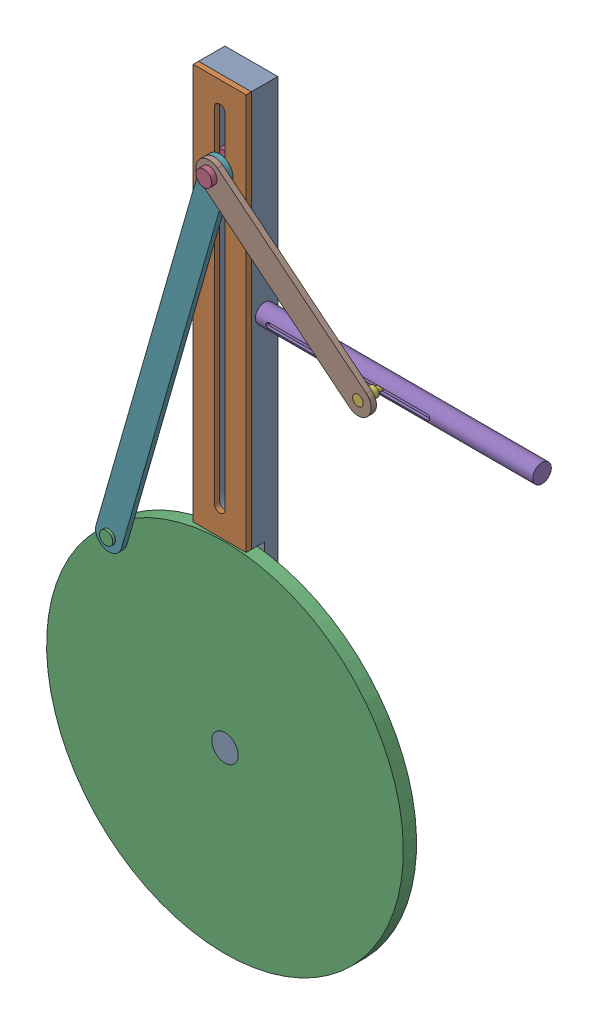
SolidWorks assembly Assem2, configuration Default. Lengths in mm.
Overall size (209.74 314.74 18).
8 component instances, 8 part files, 18 mates.
Components (placement in the parent):
- Base-1: Base [Default] at origin size (20 230 10)
- Rail Lid-1: Rail Lid [Default] at (0 -75 7) x (-1 0 0) z (0 -1 0) size (20 7 150)
- Wheel-1: Wheel [Default] at (0 -220 2.5) x (0.788618 0.614883 0) z (0 0 1) size (135 135 10)
- Cylinder Connector-1: Cylinder Connector [Default] at (0 -29.3569 0) x (-0.943808 -0.330495 0) z (-0.330495 0.943808 0) size (10 13 10)
- Piston Cylinder-1: Piston Cylinder [Default] at (50 -75 0) size (107 7 7)
- Piston-1: Piston [Default] at (56.329 -75 5) size (42 5 13.5)
- Large Link-1: Large Link [Default] at (-19.9837 -99.0484 7) x (-0.961262 0.275637 0) z (0 0 1) size (10 155 2)
- Small Link-1: Small Link [Default] at (56.329 -75 9) x (-0.62956 -0.776952 0) z (0 0 1) size (10 82.5 2)
Mates (geometry in assembly coordinates):
- Concentric1: concentric aligned: cylinder of Base-1 through (-7 -3.5 0) axis (0 0 1) radius 1.5; cylinder of Rail Lid-1 through (-7 -3.5 0) axis (0 0 1) radius 1.5
- Concentric2: concentric aligned: cylinder of Base-1 through (7 -146.5 0) axis (0 0 1) radius 1.5; cylinder of Rail Lid-1 through (7 -146.5 0) axis (0 0 1) radius 1.5
- Coincident1: coincident anti-aligned: plane of Base-1 through (0 -75 5) normal (0 0 1); plane of Rail Lid-1 through (0 -75 5) normal (0 0 -1)
- Concentric3: concentric aligned: cylinder of Base-1 through (0 -220 5) axis (0 0 -1) radius 5; cylinder of Wheel-1 through (0 -220 5) axis (0 0 -1) radius 5
- Coincident2: coincident anti-aligned: plane of Base-1 through (0 -220 0) normal (0 0 1); plane of Wheel-1 through (0 -220 0) normal (0 0 -1)
- Coincident3: coincident anti-aligned: plane of Base-1 through (0 -140 0) normal (0 0 1); plane of Cylinder Connector-1 through (0 -12.5861 0) normal (0 0 -1)
- Tangent1: tangent anti-aligned: plane of Base-1 through (-5 -140 0) normal (1 0 0); cylinder of Cylinder Connector-1 through (0 -12.5861 5) axis (0 0 -1) radius 5
- Concentric4: concentric aligned: cylinder of Base-1 through (8 -75 0) axis (1 0 0) radius 1.5; cylinder of Piston Cylinder-1 through (8 -75 0) axis (1 0 0) radius 1.5
- Coincident5: coincident anti-aligned: plane of Base-1 through (10 -150 5) normal (1 0 0); plane of Piston Cylinder-1 through (10 -75 0) normal (-1 0 0)
- Parallel1: parallel anti-aligned: plane of Base-1 through (-10 0 5) normal (0 1 0); plane of Piston Cylinder-1 through (15 -74 3.5) normal (0 -1 0)
- Concentric5: concentric aligned: cylinder of Piston Cylinder-1 through (2.9289 -75 0) axis (1 0 0) radius 2.5; cylinder of Piston-1 through (75.8885 -75 0) axis (1 0 0) radius 2.5
- Concentric6: concentric aligned: cylinder of Cylinder Connector-1 through (0 -12.5861 11) axis (0 0 -1) radius 2; cylinder of Large Link-1 through (0 -12.5861 9) axis (0 0 -1) radius 2
- Coincident7: coincident anti-aligned: plane of Large Link-1 through (0 -12.5861 7) normal (0 0 -1); plane of Rail Lid-1 through (0 -75 7) normal (0 0 1)
- Concentric7: concentric aligned: cylinder of Wheel-1 through (-15.1566 -156.7918 9) axis (0 0 -1) radius 2; cylinder of Large Link-1 through (-15.1566 -156.7918 9) axis (0 0 -1) radius 2
- Concentric8: concentric aligned: cylinder of Cylinder Connector-1 through (0 -12.5861 11) axis (0 0 -1) radius 2; cylinder of Small Link-1 through (0 -12.5861 11) axis (0 0 -1) radius 2
- Coincident8: coincident anti-aligned: plane of Large Link-1 through (0 -12.5861 9) normal (0 0 1); plane of Small Link-1 through (0 -12.5861 9) normal (0 0 -1)
- Concentric9: concentric aligned: cylinder of Piston-1 through (36.8885 -75 11) axis (0 0 -1) radius 2; cylinder of Small Link-1 through (36.8885 -75 11) axis (0 0 -1) radius 2
- Angle3: planar angle = 0.279253 rad aligned: plane of Large Link-1 through (-4.8063 -27.9787 9) normal (-0.961262 0.275637 0); plane of Base-1 through (-10 -150 5) normal (-1 0 0)
